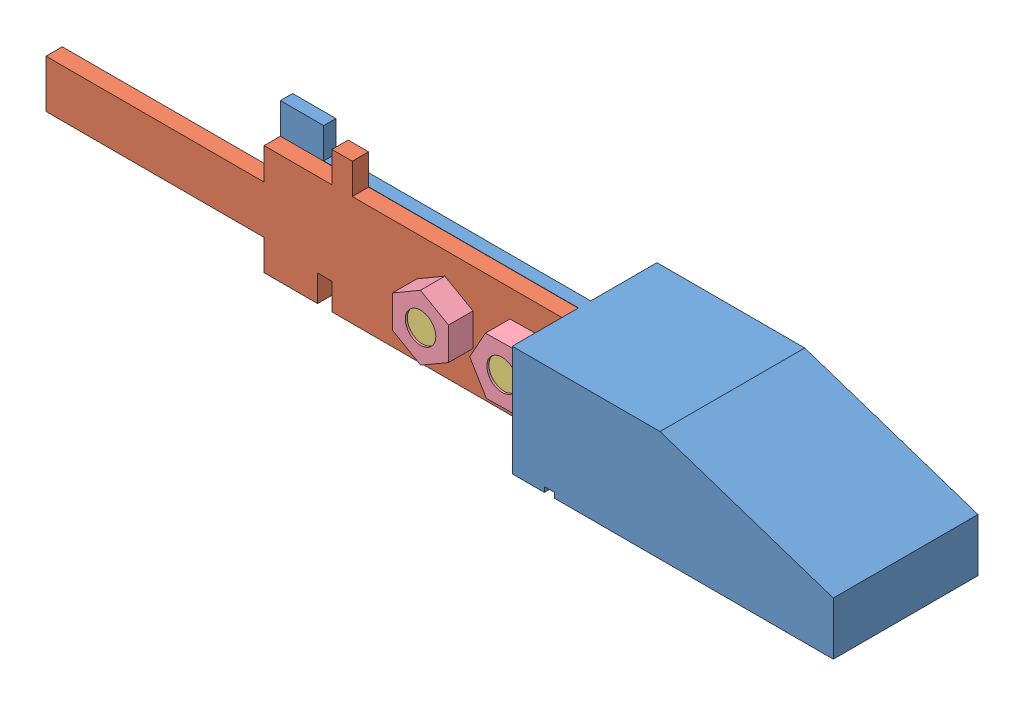
SolidWorks assembly 0202 Button_ASM, configuration Domyślna. Lengths in mm.
Overall size (82.15 13.85 14.2).
6 component instances, 4 part files, 11 mates.
Components (placement in the parent):
- 0008 Button_Mustang_radio-1: 0008 Button_Mustang_radio [Domyślna] at (23.1329 -11.9839 53.65) size (60.75 13.85 14.2)
- 0202_02 Button_pusher-1: 0202_02 Button_pusher [Domyślna] at (-73.7457 12.6375 84.3669) x (0 0 1) z (1 0 0) size (1.62 13.8 50.65)
- 0301_03 M3_5 screw-1: 0301_03 M3_5 screw [Domyślna] at (-23.1095 5.1722 60.15) x (0.994507 -0.104669 0) z (0 0 -1) size (6 6 7.48)
- 0301_03 M3_5 screw-2: 0301_03 M3_5 screw [Domyślna] at (-13.9404 2.6786 60.15) x (0.570039 -0.821618 0) z (0 0 -1) size (6 6 7.48)
- 0301_02 M3 nut-1: 0301_02 M3 nut [Domyślna] at (-17.2457 2.6499 62.95) x (0.871112 -0.491084 0) z (0 0 1) size (5.51 6.35 2.4)
- 0301_02 M3 nut-2: 0301_02 M3 nut [Domyślna] at (-25.2457 2.6499 62.95) size (5.51 6.35 2.4)
Mates (geometry in assembly coordinates):
- Koncentryczne1: concentric aligned: circle of 0008 Button_Mustang_radio-1; cylinder of 0202_02 Button_pusher-1 through (-17.2457 2.6499 2.95) axis (0 0 1) radius 1.25
- Koncentryczne2: concentric anti-aligned: circle of 0008 Button_Mustang_radio-1; circle of 0202_02 Button_pusher-1
- Wspólnie1: coincident anti-aligned: plane of 0008 Button_Mustang_radio-1 through (-42.9957 8.0799 61.35) normal (0 0 1); plane of 0202_02 Button_pusher-1 through (-13.7457 -2.7501 61.35) normal (0 0 -1)
- Koncentryczne3: concentric anti-aligned: circle of 0008 Button_Mustang_radio-1; cylinder of 0301_03 M3_5 screw-2 through (-17.2457 2.6499 65.15) axis (0 0 -1) radius 1.5
- Koncentryczne4: concentric aligned: circle of 0202_02 Button_pusher-1; circle of 0301_03 M3_5 screw-1
- Wspólnie2: coincident anti-aligned: plane of 0008 Button_Mustang_radio-1 through (-42.9957 8.0799 60.15) normal (0 0 -1); plane of 0301_03 M3_5 screw-2 through (-17.2457 2.6499 60.15) normal (0 0 1)
- Wspólnie3: coincident aligned: plane of 0008 Button_Mustang_radio-1 through (-42.9957 8.0799 60.15) normal (0 0 -1); circle of 0301_03 M3_5 screw-1
- Koncentryczne6: concentric aligned: cylinder of 0301_03 M3_5 screw-2 through (-17.2457 2.6499 65.15) axis (0 0 -1) radius 1.5; cylinder of 0301_02 M3 nut-1 through (-17.2457 2.6499 65.35) axis (0 0 -1) radius 1.4964
- Wspólnie6: coincident anti-aligned: plane of 0202_02 Button_pusher-1 through (-13.7457 -2.7501 62.95) normal (0 0 1); plane of 0301_02 M3 nut-1 through (-17.2457 2.6499 62.95) normal (0 0 -1)
- Koncentryczne7: concentric aligned: cylinder of 0301_03 M3_5 screw-1 through (-25.2457 2.6499 65.15) axis (0 0 -1) radius 1.5; cylinder of 0301_02 M3 nut-2 through (-25.2457 2.6499 65.35) axis (0 0 -1) radius 1.4964
- Wspólnie7: coincident anti-aligned: plane of 0202_02 Button_pusher-1 through (-13.7457 -2.7501 62.95) normal (0 0 1); plane of 0301_02 M3 nut-2 through (-25.2457 2.6499 62.95) normal (0 0 -1)
